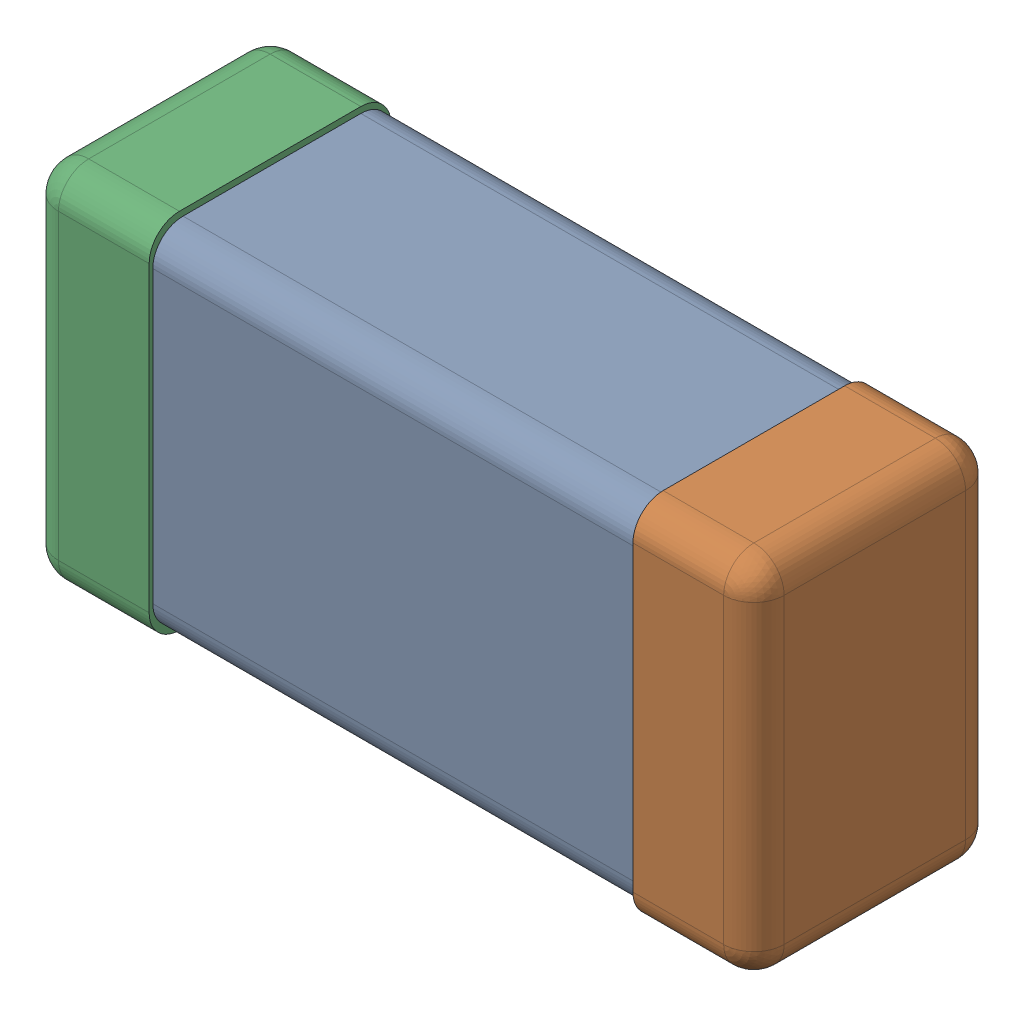
SolidWorks assembly C0201_020_5, configuration Standard. Lengths in mm.
Overall size (0.6 0.3 0.2).
3 component instances, 3 part files, 0 mates.
Components (placement in the parent):
- Part 3_2-1: Part 3_2 [Standard] at (0 0 -7.3015) size (0.5 0.29 0.2)
- Part 2_2-1: Part 2_2 [Standard] at (0 0 -7.3) size (0.1 0.3 0.2)
- Part 1_2-1: Part 1_2 [Standard] at (0 0 -7.3) size (0.1 0.3 0.2)
